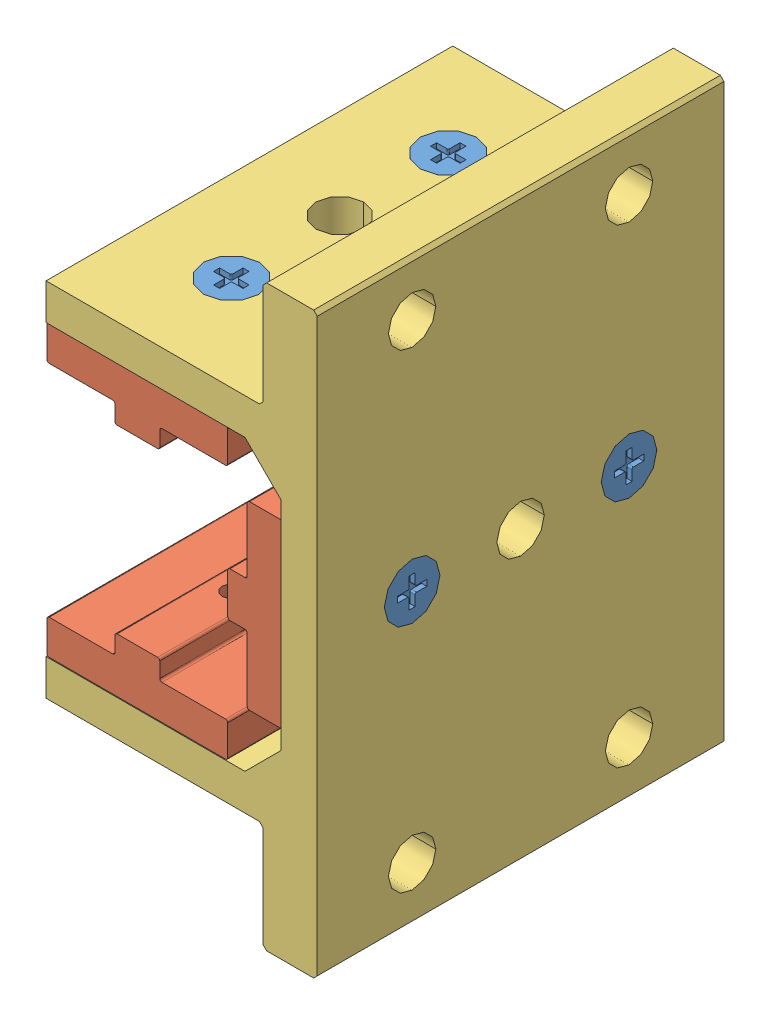
SolidWorks assembly 6525_linearBearing, configuration Default. Lengths in mm.
Overall size (47.63 101.6 71.42).
10 component instances, 3 part files, 0 mates.
Components (placement in the parent):
- 6525_3-1: 6525_3 [Default] at (0 -29.7892 -19.05) size (9.78 2.08 9.78)
- 6525_3-2: 6525_3 [Default] at (0 -29.7892 19.05) size (9.78 2.08 9.78)
- 6525_3-3: 6525_3 [Default] at (0 29.7892 -19.05) x (1 0 0) z (0 0 -1) size (9.78 2.08 9.78)
- 6525_3-4: 6525_3 [Default] at (0 29.7892 19.05) x (1 0 0) z (0 0 -1) size (9.78 2.08 9.78)
- 6525_3-5: 6525_3 [Default] at (29.7892 0 -19.05) x (0 0 -1) z (0 1 0) size (9.78 2.08 9.78)
- 6525_3-6: 6525_3 [Default] at (29.7892 0 19.05) x (0 0 -1) z (0 1 0) size (9.78 2.08 9.78)
- 6525_10-1: 6525_10 [Default] at (0 -19.304 0) x (0 -1 0) z (0 0 1) size (9.53 31.75 71.12)
- 6525_10-2: 6525_10 [Default] at (0 19.304 0) x (0 1 0) z (0 0 1) size (9.53 31.75 71.12)
- 6525_10-3: 6525_10 [Default] at (19.304 0 0) size (9.53 31.75 71.12)
- 6525_14-1: 6525_14 [Default] at origin size (47.63 101.6 71.42)
